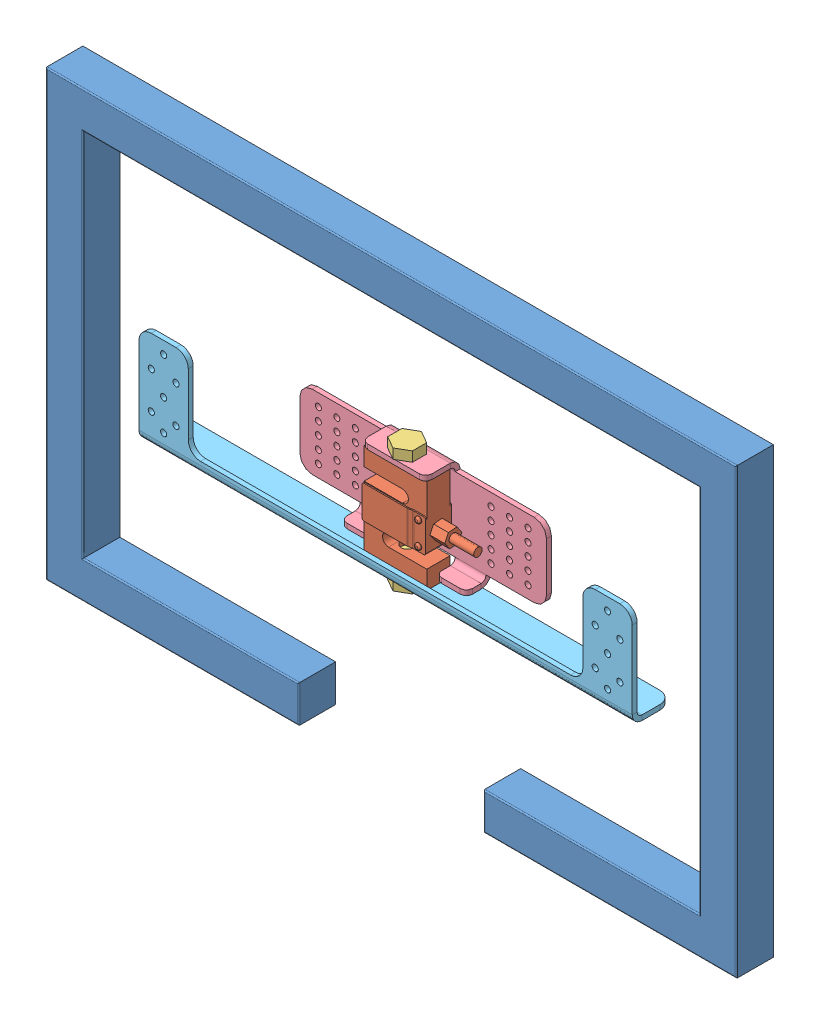
SolidWorks assembly WallBench - Assembly v2, configuration Default. Lengths in mm.
Overall size (560 360 34.5).
9 component instances, 8 part files, 31 mates.
Components (placement in the parent):
- WallBench - Frame-1: WallBench - Frame [Default] at (-897.0742 586.6756 0) size (560 360 30)
- WallBench - Galga-1: WallBench - Galga [Default] at (-897.0742 588.4256 7.5) x (1 0 0) z (0 -1 0) size (82.8 24.7 76.5)
- Tornillo_M12-1: Tornillo_M12 [Default] at (-897.0742 638.6756 17) x (0.845145 0 -0.534536) z (-0.534536 0 -0.845145) size (23.08 23 20.45)
- Wall-1: Wall [Default] at (-897.0742 586.6756 -10) x (1 0 0) z (0 -1 0) size (2000 10 1000) (hidden)
- WallBench - Main supoport v2-1: WallBench - Main supoport v2 [Default] at (-897.0742 592.6756 4) x (1 0 0) z (0 -1 0) size (200 28 76)
- Tornillo_M12-2: Tornillo_M12 [Default] at (-897.0742 538.1756 17) x (0.040349 0 -0.999186) z (0.999186 0 0.040349) size (23.08 23 20.45)
- WallBench - L Support v2-1: WallBench - L Support v2 [Default] at (-897.0742 550.1756 54.75) size (400 81 32.5)
- Fingerboard_v2-1: Fingerboard_v2 [Default] at (-993.7852 521.7294 44.5) size (150 110 40) (hidden)
- WallBench - Moving wall-2: WallBench - Moving wall [Default] at (-899.0101 589.0914 44.5) x (1 0 0) z (0 1 0) size (495 10 295) (hidden)
Mates (geometry in assembly coordinates):
- Coincidente1: coincident anti-aligned: plane of WallBench - Frame-1 through (-902.6231 586.6756 0) normal (0 0 -1); plane of assembly through (0 0 0) normal (0 0 1)
- Coincidente2: coincident anti-aligned: plane of WallBench - Frame-1 through (-902.6231 586.6756 0) normal (0 0 -1); plane of Wall-1 through (-902.6231 586.6756 0) normal (0 0 1)
- Distancia1: distance = 320 mm aligned: plane of WallBench - Frame-1 through (-1177.0742 766.6756 30) normal (0 1 0); plane of Wall-1 through (-1897.0742 1086.6756 0) normal (0 1 0)
- Coincidente4: coincident anti-aligned: plane of Wall-1 through (-902.6231 586.6756 0) normal (0 0 1); plane of WallBench - Main supoport v2-1 through (-923.6231 645.6756 0) normal (0 0 -1)
- Coincidente5: coincident anti-aligned: plane of WallBench - Galga-1 through (-928.0231 626.6756 26.5) normal (0 1 0); plane of WallBench - Main supoport v2-1 through (-923.6231 626.6756 23) normal (0 -1 0)
- Paralelo1: parallel aligned: plane of WallBench - Galga-1 through (-908.2231 570.1756 26.5) normal (0 0 1); plane of WallBench - Main supoport v2-1 through (-923.6231 630.6756 28) normal (0 0 1)
- Concéntrica3: concentric anti-aligned: cylinder of WallBench - Galga-1 through (-902.6231 623.4132 15) axis (0 -1 0) radius 5; cylinder of ? through (-902.6231 536.9122 15) axis (0 1 0) radius 6
- Coincidente6: coincident anti-aligned: plane of WallBench - Galga-1 through (-928.0231 546.9122 24.5) normal (0 -1 0); plane of ? through (-1092.6231 546.9122 55) normal (0 1 0)
- Paralelo2: parallel aligned: plane of WallBench - Galga-1 through (-908.2231 566.9122 24.5) normal (0 0 1); plane of ? through (-1092.6231 574.3501 28.7366) normal (0 0 1)
- Coincidente8: coincident anti-aligned: plane of ? through (-1092.6231 574.3501 28.7366) normal (0 0 1); plane of ? through (-903.6457 587.3832 28.7366) normal (0 0 -1)
- Coincidente9: coincident anti-aligned: plane of ? through (-903.6457 587.3832 58.7366) normal (0 0 1); plane of ? through (-954.1457 526.8832 58.7366) normal (0 0 -1)
- Concéntrica4: concentric anti-aligned: cylinder of WallBench - Galga-1 through (-902.6231 550.1746 17) axis (0 1 0) radius 5; cylinder of WallBench - Main supoport v2-1 through (-902.6231 630.6766 17) axis (0 -1 0) radius 7
- Concéntrica5: concentric anti-aligned: cylinder of Tornillo_M12-1 through (-902.6231 615.6756 17) axis (0 1 0) radius 6; cylinder of WallBench - Main supoport v2-1 through (-902.6231 630.6766 17) axis (0 -1 0) radius 7
- Coincidente10: coincident anti-aligned: plane of Tornillo_M12-1 through (-902.6231 630.6756 17) normal (0 -1 0); plane of WallBench - Main supoport v2-1 through (-923.6231 630.6756 23) normal (0 1 0)
- Paralelo3: parallel aligned: plane of Tornillo_M12-1 through (-892.6231 630.6756 11.2265) normal (1 0 0); plane of WallBench - Main supoport v2-1 through (-876.6231 630.6756 0) normal (1 0 0)
- Concéntrica7: concentric anti-aligned: cylinder of ? through (-902.6231 536.9122 15) axis (0 1 0) radius 6; cylinder of Tornillo_M12-2 through (-902.6231 557.9122 15) axis (0 -1 0) radius 6
- Coincidente12: coincident anti-aligned: plane of ? through (-1092.6231 542.9122 55) normal (0 -1 0); plane of Tornillo_M12-2 through (-902.6231 542.9122 15) normal (0 1 0)
- Perpendicular1: perpendicular: plane of ? through (-1092.6231 574.3501 28.7366) normal (0 0 1); plane of Tornillo_M12-2 through (-892.6231 542.9122 20.7735) normal (1 0 0)
- Distancia2: distance = 720 mm aligned: plane of WallBench - Frame-1 through (-1177.0742 766.6756 30) normal (-1 0 0); plane of Wall-1 through (-1897.0742 1086.6756 0) normal (-1 0 0)
- Distancia5: distance = 150 mm anti-aligned: plane of WallBench - Frame-1 through (-1147.0742 736.6756 30) normal (1 0 0); plane of WallBench - Main supoport v2-1 through (-997.0742 612.6756 0) normal (-1 0 0)
- Distancia6: distance = 114 mm anti-aligned: plane of WallBench - Main supoport v2-1 through (-987.0742 622.6756 0) normal (0 1 0); plane of WallBench - Frame-1 through (-1147.0742 736.6756 30) normal (0 -1 0)
- Distancia7: distance = 98 mm aligned: plane of ? through (-954.1457 636.8832 58.7366) normal (0 1 0); plane of ? through (-1151.1457 734.8832 48.7366) normal (0 1 0)
- Distancia8: distance = 47 mm aligned: plane of ? through (-1104.1457 583.6759 82.7366) normal (-1 0 0); plane of ? through (-1151.1457 439.8832 48.7366) normal (-1 0 0)
- Coincidente15: coincident anti-aligned: plane of ? through (-1092.6231 574.3501 28.7366) normal (0 0 1); plane of ? through (-903.6457 587.3832 28.7366) normal (0 0 -1)
- Concéntrica8: concentric anti-aligned: cylinder of WallBench - Galga-1 through (-902.6231 626.6766 17) axis (0 -1 0) radius 5; cylinder of WallBench - L Support v2-1 through (-902.6231 540.1756 17) axis (0 1 0) radius 7
- Coincidente16: coincident anti-aligned: plane of WallBench - Galga-1 through (-928.0231 550.1756 26.5) normal (0 -1 0); plane of WallBench - L Support v2-1 through (-1092.6231 550.1756 97.5) normal (0 1 0)
- Paralelo5: parallel aligned: plane of WallBench - Galga-1 through (-908.2231 570.1756 26.5) normal (0 0 1); plane of WallBench - L Support v2-1 through (-1092.6231 617.1756 34.5) normal (0 0 1)
- Coincidente17: coincident anti-aligned: plane of WallBench - L Support v2-1 through (-1092.6231 617.1756 34.5) normal (0 0 1); plane of WallBench - Moving wall-2 through (-899.0101 589.0914 34.5) normal (0 0 -1)
- Coincidente18: coincident anti-aligned: plane of Fingerboard_v2-1 through (-843.7852 521.7294 44.5) normal (0 0 -1); plane of WallBench - Moving wall-2 through (-899.0101 589.0914 44.5) normal (0 0 1)
- Concéntrica9: concentric: cylinder of Tornillo_M12-2 through (-897.0742 561.1756 17) axis (0 -1 0) radius 6; cylinder of WallBench - L Support v2-1 through (-897.0742 540.1756 17) axis (0 1 0) radius 7
- Coincidente19: coincident anti-aligned: plane of Tornillo_M12-2 through (-897.0742 546.1756 17) normal (0 1 0); plane of WallBench - L Support v2-1 through (-1087.0742 546.1756 97.5) normal (0 -1 0)
